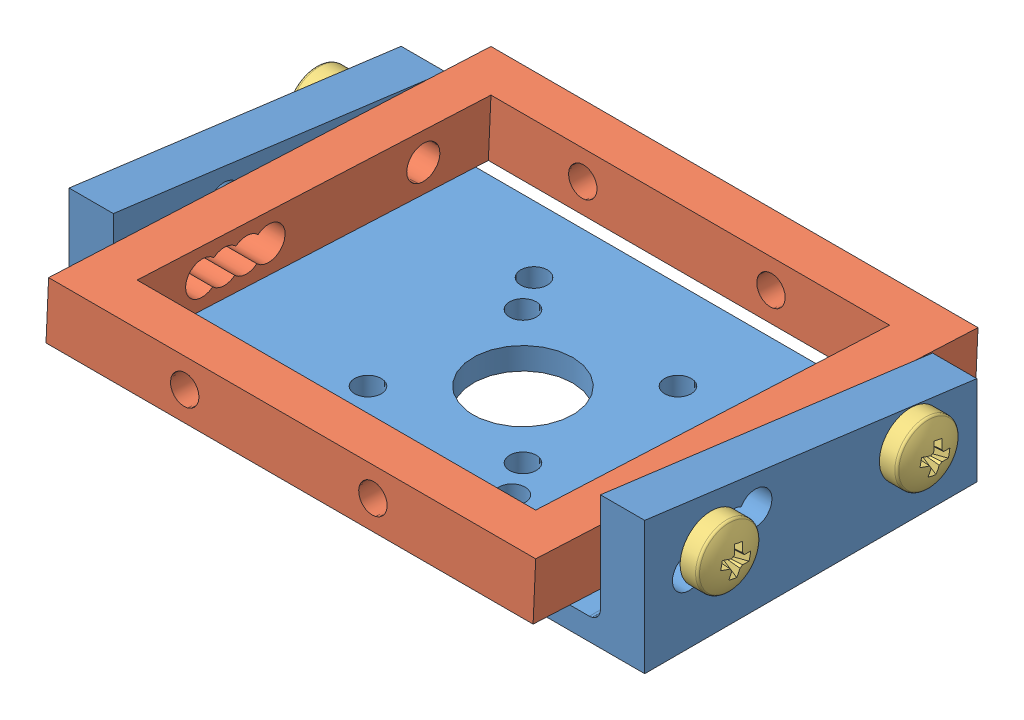
SolidWorks assembly Montagem1, configuration Valor predeterminado. Lengths in mm.
Overall size (56.71 12 40.19).
6 component instances, 3 part files, 9 mates.
Components (placement in the parent):
- suporte_inclinado_base_2-1: suporte_inclinado_base_2 [Valor predeterminado] at (-4.5031 -10.0444 52) size (52 12 30)
- suporte_inclinado_haste_2-1: suporte_inclinado_haste_2 [Valor predeterminado] at (-22.5031 -3.5719 52.9888) x (0 0.047259 0.998883) z (-1 0 0) size (40 5 44)
- pan head cross recess screw_iso-1: pan head cross recess screw_iso [ISO 7045 - M3 x 4 - Z --- 4N] at (-32.9031 -4.0444 43) x (1 0 0) z (0 -0.729485 -0.683997) size (6.35 5.6 5.6)
- pan head cross recess screw_iso-2: pan head cross recess screw_iso [ISO 7045 - M3 x 4 - Z --- 4N] at (-32.9031 -3.1044 61) x (1 0 0) z (0 -0.42501 -0.905189) size (6.35 5.6 5.6)
- pan head cross recess screw_iso-3: pan head cross recess screw_iso [ISO 7045 - M3 x 4 - Z --- 4N] at (23.8969 -3.1044 61) x (-1 0 0) z (0 0.979139 -0.20319) size (6.35 5.6 5.6)
- pan head cross recess screw_iso-4: pan head cross recess screw_iso [ISO 7045 - M3 x 4 - Z --- 4N] at (23.8969 -4.0444 43) x (-1 0 0) z (0 0.979139 -0.20319) size (6.35 5.6 5.6)
Mates (geometry in assembly coordinates):
- Coincidente2: coincident aligned: circle of suporte_inclinado_base_2-1; circle of suporte_inclinado_haste_2-1
- Concêntrico2: concentric aligned: circle of suporte_inclinado_base_2-1; circle of pan head cross recess screw_iso-1
- Coincidente4: coincident anti-aligned: plane of suporte_inclinado_base_2-1 through (-30.5031 -8.0444 67) normal (-1 0 0); plane of pan head cross recess screw_iso-1 through (-30.5031 -5.0704 44.0942) normal (1 0 0)
- Concêntrico4: concentric aligned: cylinder of suporte_inclinado_base_2-1 through (-26.5031 -3.1044 61) axis (-1 0 0) radius 1.5; cylinder of pan head cross recess screw_iso-2 through (-58.3031 -3.1044 61) axis (-1 0 0) radius 1.5
- Coincidente7: coincident anti-aligned: plane of suporte_inclinado_base_2-1 through (-30.5031 -8.0444 67) normal (-1 0 0); plane of pan head cross recess screw_iso-2 through (-30.5031 -4.4622 61.6375) normal (1 0 0)
- Concêntrico5: concentric: cylinder of suporte_inclinado_base_2-1 through (17.4969 -3.1044 61) axis (1 0 0) radius 1.5; cylinder of pan head cross recess screw_iso-3 through (49.2969 -3.1044 61) axis (1 0 0) radius 1.5
- Coincidente9: coincident anti-aligned: plane of suporte_inclinado_base_2-1 through (21.4969 -8.0444 67) normal (1 0 0); plane of pan head cross recess screw_iso-3 through (21.4969 -2.7997 62.4687) normal (-1 0 0)
- Concêntrico6: concentric: cylinder of suporte_inclinado_base_2-1 through (17.4969 -4.0444 43) axis (1 0 0) radius 1.5; cylinder of pan head cross recess screw_iso-4 through (49.2969 -4.0444 43) axis (1 0 0) radius 1.5
- Coincidente10: coincident anti-aligned: plane of suporte_inclinado_base_2-1 through (21.4969 -8.0444 67) normal (1 0 0); plane of pan head cross recess screw_iso-4 through (21.4969 -3.7397 44.4687) normal (-1 0 0)
